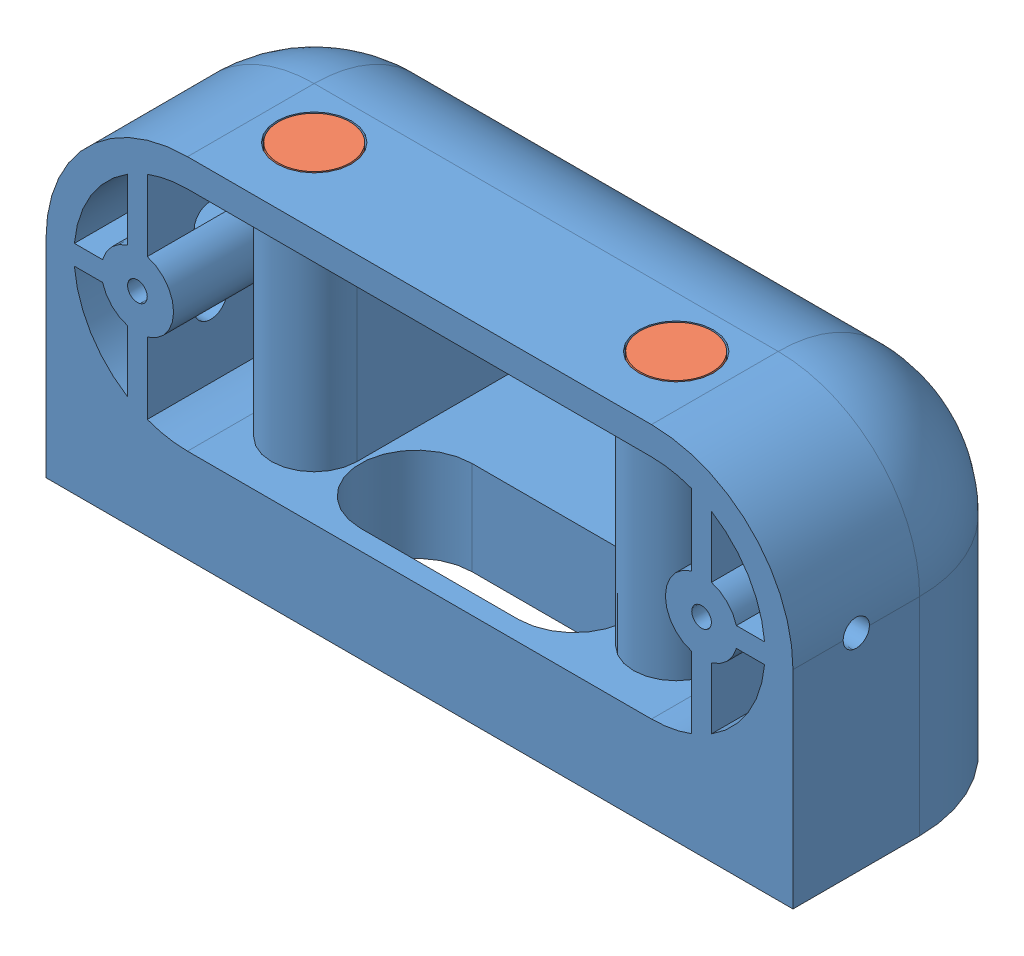
SolidWorks assembly 90DegDoorbell, configuration Default. Lengths in mm.
Overall size (113.5 53 40.75).
3 component instances, 2 part files, 5 mates.
Components (placement in the parent):
- mainBody-1: mainBody [Default] at origin size (113.5 53 40.75)
- cap-1: cap [Default] at origin size (10.85 2.5 10.85)
- cap-2: cap [Default] at (55 0 0) size (10.85 2.5 10.85)
Mates (geometry in assembly coordinates):
- Coincident1: coincident aligned: plane of mainBody-1 through (0 0 0) normal (0 0 1)
- Coincident2: coincident aligned: plane of mainBody-1 through (0 0 0) normal (0 1 0)
- Coincident3: coincident aligned: plane of mainBody-1 through (0 0 0) normal (1 0 0)
- Concentric1: concentric aligned: cylinder of mainBody-1 through (27.5 53 -11.5) axis (0 1 0) radius 5.675; cylinder of cap-2 through (27.5 34.6558 -11.5) axis (0 1 0) radius 5.425
- Coincident4: coincident aligned: plane of mainBody-1 through (0 53 0) normal (0 1 0); plane of cap-2 through (27.5 53 -11.5) normal (0 1 0)
